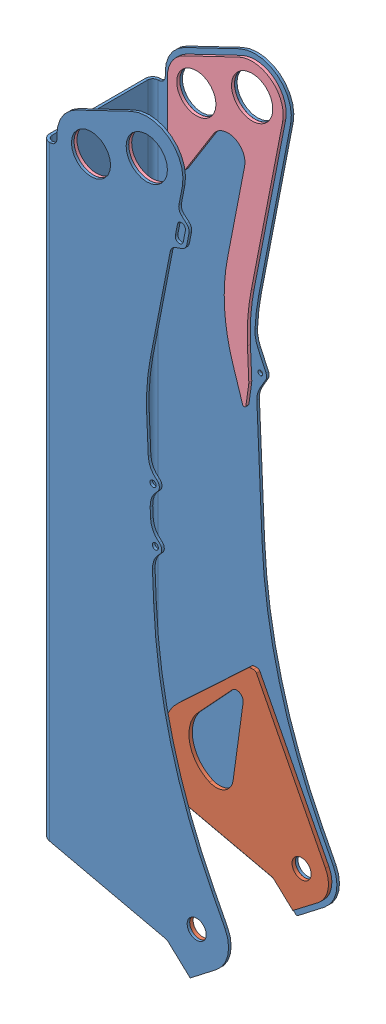
SolidWorks assembly 6344053, configuration Default. Lengths in mm.
Overall size (566.48 1735.19 260.58).
6 component instances, 4 part files, 16 mates.
Components (placement in the parent):
- 6344054-1: 6344054 [Default] at origin size (438.19 1703.77 260.58)
- 6344055-2: 6344055 [6344055] at (480 -4.567 246.3777) x (0.974956 -0.222399 0) z (0 0 1) size (406.29 417 8)
- 6344055-1: 6344055 [6344056] at (480 -4.567 6) x (0.974956 -0.222399 0) z (0 0 1) size (406.29 417 8)
- 6344057-1: 6344057 [Default med affasning + nedslibning af spids] at (122.8111 3 130.1889) x (0 -1 0) z (1 0 0) size (320 185 10)
- 6344058-1: 6344058 [Default] at (362.8595 1505.2986 6) x (0.974956 -0.222399 0) z (0 0 1) size (310 700 7)
- 6344058-2: 6344058 [Default] at (362.8595 1505.2986 247.3777) x (0.974956 -0.222399 0) z (0 0 1) size (310 700 7)
Mates (geometry in assembly coordinates):
- Concentric1: concentric aligned: cylinder of 6344054-1 through (362.8595 1505.2986 6) axis (0 0 -1) radius 48.5; cylinder of 6344058-1 through (362.8595 1505.2986 13) axis (0 0 -1) radius 48.5
- Concentric2: concentric aligned: cylinder of 6344054-1 through (231.8356 1448.0033 6) axis (0 0 -1) radius 46; cylinder of 6344058-1 through (231.8356 1448.0033 13) axis (0 0 -1) radius 46
- Coincident1: coincident anti-aligned: circle of 6344054-1; plane of 6344058-1 through (231.8356 1448.0033 6) normal (0 0 -1)
- Coincident2: coincident anti-aligned: circle of 6344054-1; plane of 6344058-2 through (231.8356 1448.0033 254.3777) normal (0 0 1)
- Concentric3: concentric anti-aligned: cylinder of 6344054-1 through (362.8595 1505.2986 254.3777) axis (0 0 1) radius 48.5; cylinder of 6344058-2 through (362.8595 1505.2986 254.3777) axis (0 0 -1) radius 48.5
- Concentric4: concentric anti-aligned: cylinder of 6344054-1 through (231.8356 1448.0033 254.3777) axis (0 0 1) radius 46; cylinder of 6344058-2 through (231.8356 1448.0033 254.3777) axis (0 0 -1) radius 46
- Coincident10: coincident anti-aligned: circle of 6344054-1; plane of 6344055-1 through (480 -4.567 6) normal (0 0 -1)
- Concentric5: concentric aligned: cylinder of 6344054-1 through (480 -4.567 6) axis (0 0 -1) radius 75; cylinder of 6344055-1 through (480 -4.567 14) axis (0 0 -1) radius 63
- Parallel1: parallel aligned: plane of 6344054-1 through (121.5979 -0.2504 6) normal (-0.222399 -0.974956 0); plane of 6344055-1 through (154.8151 -4.7506 14) normal (-0.222399 -0.974956 0)
- Distance1: distance = 3 mm aligned: plane of 6344054-1 through (122.8111 0 249.5628) normal (0 -1 0); plane of 6344057-1 through (132.8111 3 221.6889) normal (0 -1 0)
- Coincident14: coincident aligned: plane of 6344057-1 through (122.8111 3 130.1889) normal (0 0 -1)
- Coincident15: coincident anti-aligned: circle of 6344054-1; plane of 6344055-2 through (480 -4.567 254.3777) normal (0 0 1)
- Concentric6: concentric anti-aligned: cylinder of 6344054-1 through (480 -4.567 254.3777) axis (0 0 1) radius 75; cylinder of 6344055-2 through (480 -4.567 254.3777) axis (0 0 -1) radius 63
- Parallel2: parallel aligned: plane of 6344054-1 through (121.5979 -0.2504 254.3777) normal (-0.222399 -0.974956 0); plane of 6344055-2 through (154.8151 -4.7506 254.3777) normal (-0.222399 -0.974956 0)
- Coincident16 - opbukket: coincident anti-aligned: plane of 6344054-1 through (0 0 130.1889) normal (0 0 1); plane of 6344057-1 through (122.8111 3 130.1889) normal (0 0 -1)
- Coincident16: coincident: line of 6344054-1 through (122.8111 0 242.3777) axis (0 0 -1); plane of 6344057-1 through (122.8111 228 130.1889) normal (-1 0 0)
